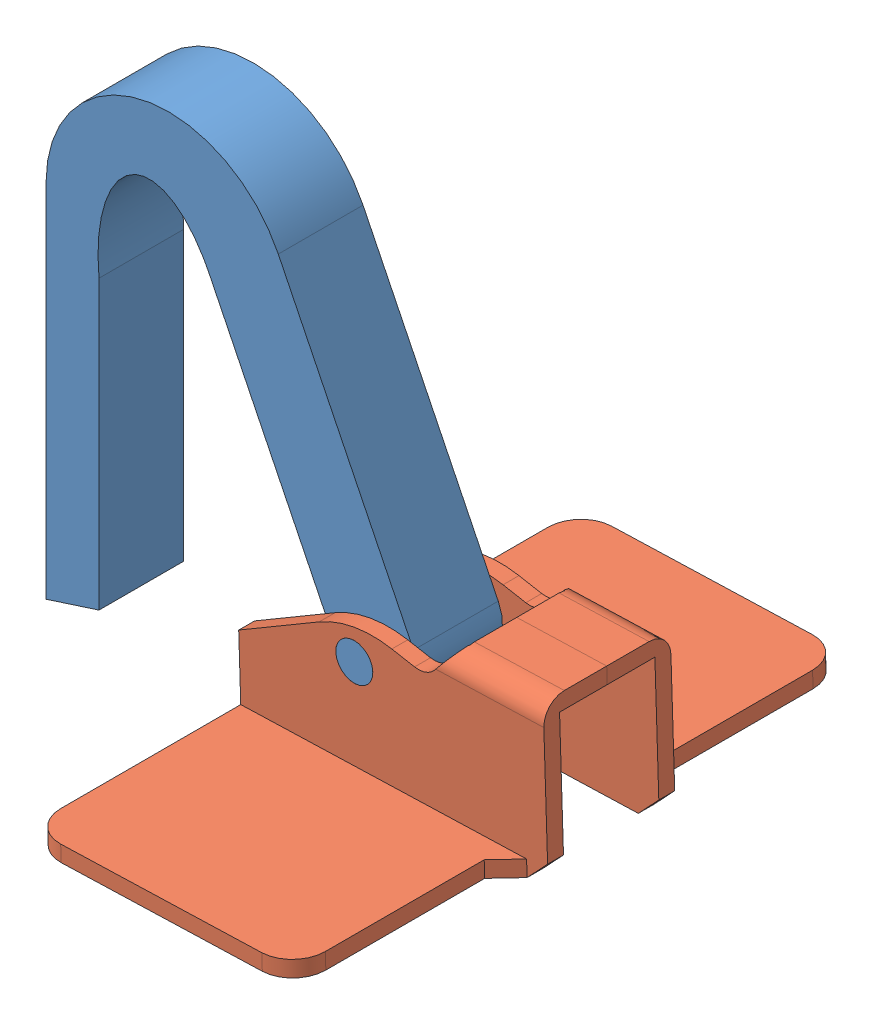
SolidWorks assembly rara, configuration Predeterminado. Lengths in mm.
Overall size (49.42 45.65 52).
2 component instances, 2 part files, 3 mates.
Components (placement in the parent):
- piezarara2-1: piezarara2 [Predeterminado] at origin size (35.1 45.65 12)
- Piezarara-1: Piezarara [Predeterminado] at (12.9492 -8.66 17.144) x (0.999481 0.032227 0) z (0 0 1) size (29 15 52)
Mates (geometry in assembly coordinates):
- Concéntrica2: concentric aligned: cylinder of piezarara2-1 through (-12.4503 0.5262 -2) axis (0 0 1) radius 1.75; cylinder of Piezarara-1 through (-12.4503 0.5262 -22.0011) axis (0 0 1) radius 1.75
- Concéntrica4: concentric anti-aligned: cylinder of piezarara2-1 through (-12.4503 0.5262 10) axis (0 0 -1) radius 1.75; circle of Piezarara-1
- Coincidente4: coincident aligned: plane of piezarara2-1 through (-12.4503 0.5262 -2) normal (0 0 -1); circle of Piezarara-1
